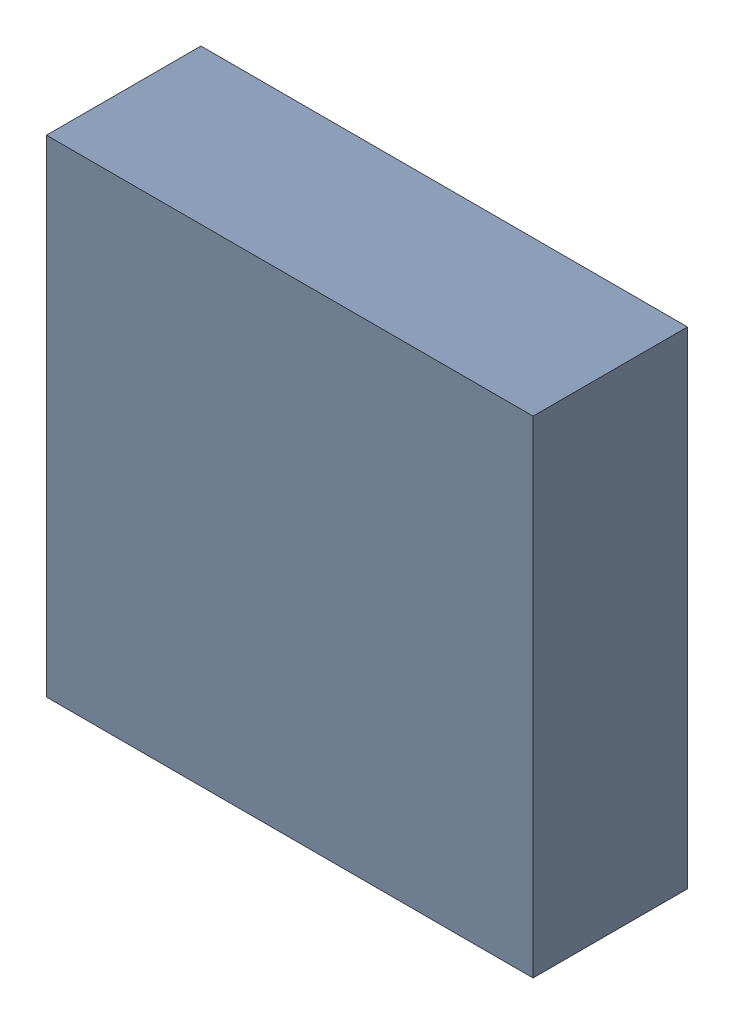
SolidWorks assembly U22, configuration Default. Lengths in mm.
Overall size (3.15 3.15 1).
2 component instances, 1 part files, 0 mates.
Components (placement in the parent):
- 836758384-1: 836758384 [Default] at (111.15 62.8 0) size (3.15 3.15 1)
  - Extruded_39-1: Extruded_39 [Default] at origin size (3.15 3.15 1)
